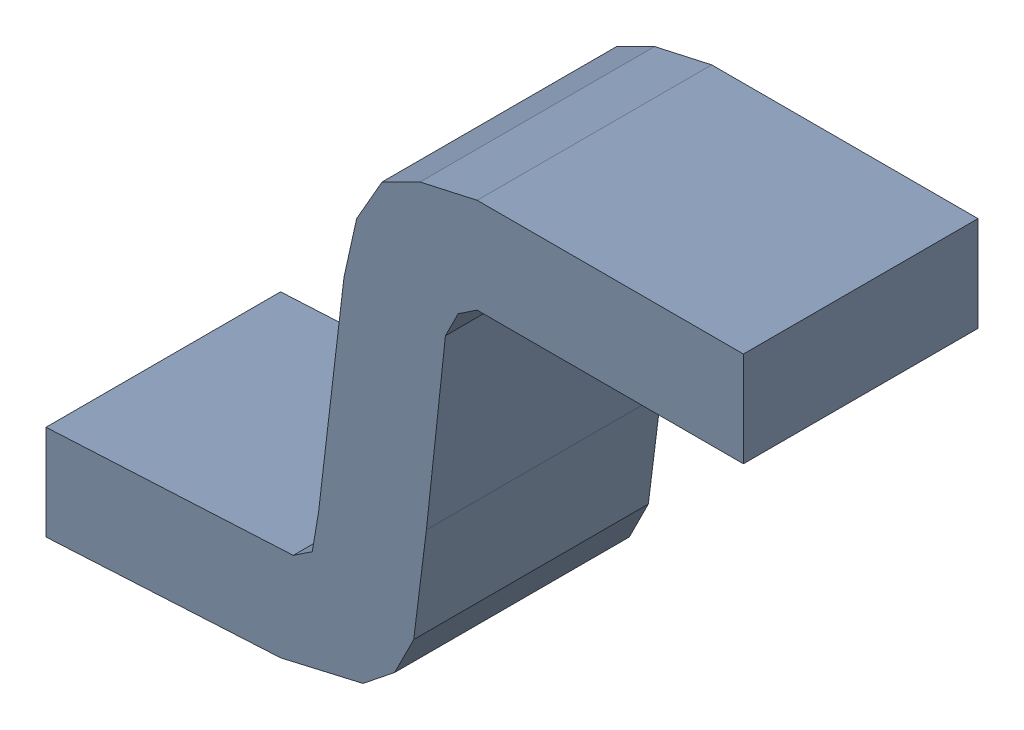
SolidWorks assembly SW3dPS-LQFP32_Free-Models3, configuration Default. Lengths in mm.
Overall size (1.1 0.8 0.37).
2 component instances, 1 part files, 0 mates.
Components (placement in the parent):
- SW3dPS-LQFP32_450941905-1: SW3dPS-LQFP32_450941905 [Default] at (-0.54 -0.325 -0.3573) size (1.1 0.8 0.37)
  - SW3dPS-LQFP32_Extruded15-1: SW3dPS-LQFP32_Extruded15 [Default] at origin size (1.1 0.8 0.37)
